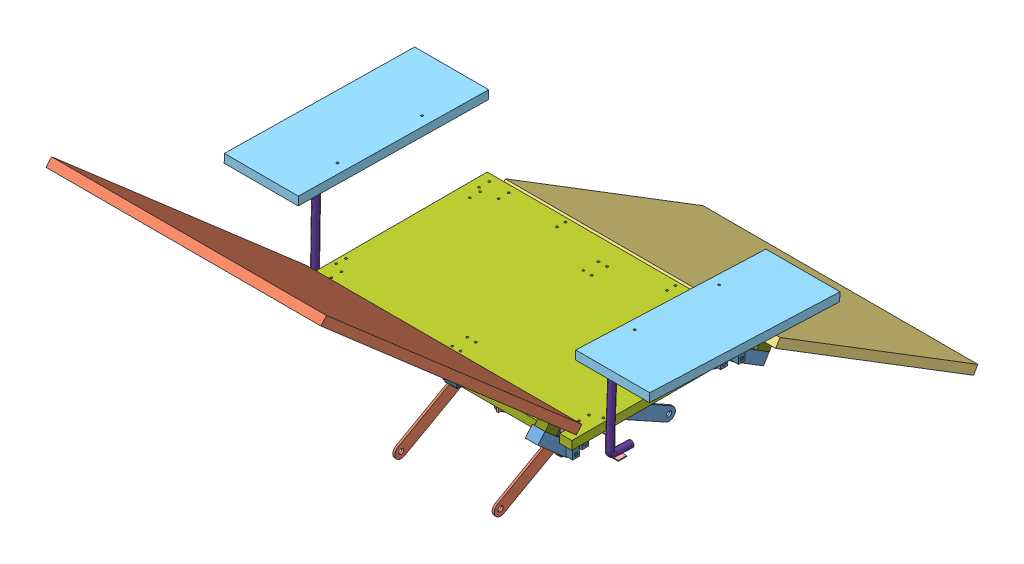
SolidWorks assembly shang, configuration 默认. Lengths in mm.
Overall size (1000 887.42 1553.51).
66 component instances, 23 part files, 0 mates.
Components (placement in the parent):
- 零件71-1: 零件71 [默认] at (-136.5896 263.2791 625.8551) x (0 -0.874201 0.485564) z (1 0 0) size (30 480 5)
- 零件7-5: 零件7 [默认] at (-126.5896 -56.9582 625.8551) x (0 0.874201 0.485564) z (-1 0 0) size (30 480 5)
- 零件7-6: 零件7 [默认] at (103.4104 -16.1101 648.5436) x (0 -0.874201 -0.485564) z (1 0 0) size (30 480 5)
- 零件71-3: 零件71 [默认] at (108.4104 263.2791 625.8551) x (0 -0.874201 0.485564) z (1 0 0) size (30 480 5)
- 滑块·1-3: 滑块·1 [默认] at (146.0969 224.4122 603.9442) x (1 0 0) z (0 1 0) size (20 28.9 7)
- 零件6-3: 零件6 [默认] at (80.2524 224.4122 600.5289) x (0 0 -1) z (0 -1 0) size (28.9 20 22)
- 滑轨-4: 滑轨 [默认] at (106.5244 234.4122 471.9365) x (-1 0 0) z (0 -1 0) size (10 150 6.5)
- 零件8-3: 零件8 [默认] at (126.9036 234.4122 204.8219) x (0 0 1) z (0 -1 0) size (30 20 32)
- 装配体5-1: 装配体5 [默认] at (-21.003 894.4122 308.3824) x (0 0 -1) z (0 -1 0) size (450 650 75.63)
  - 座板5-1: 座板5 [默认] at (-85.6176 9.4134 640) size (450 650 20)
  - 角度电机支架-1: 角度电机支架 [默认] at (41.3824 -11.5866 660) x (0 1 0) z (1 0 0) size (37 50 56)
  - spur gear_gb-1: spur gear_gb [GB - Spur gear 1M 32T 20PA 10FW ---S32A75H50L8.0N] at (110.3824 -265.5866 691.77) x (0 -1 0) z (-0.637461 0 0.770483) size (10 33.89 33.89)
  - spur gear_gb-2: spur gear_gb [GB - Spur gear 1M 32T 20PA 10FW ---S32A75H50L8.0N] at (78.3824 -265.5866 691.7667) x (0 -1 0) z (0 0 1) size (10 33.89 33.89)
  - 角电机减速机1-1: 角电机减速机1 [默认] at (69.2824 -6.5866 691.7667) x (1 0 0) z (0 -1 0) size (58.2 40 66)
  - 角度电机-1: 角度电机 [默认] at (40.1824 4.9134 693.7667) x (-1 0 0) z (0 -0.900769 -0.434299) size (74 31 31)
  - 联轴器2-1: 联轴器2 [默认] at (78.3824 -33.0866 691.7667) x (-0.028487 0 0.999594) z (0 1 0) size (16 16 40)
  - 轴-1: 轴 [默认] at (78.3824 -291.5866 691.7667) x (0.269951 0 -0.962874) z (0 1 0) size (8 8 251.5)
  - 支柱1-1: 支柱1 [默认] at (78.3824 -275.5866 660) x (1 0 0) z (0 -1 0) size (32 40 16)
  - 支柱1-2: 支柱1 [默认] at (110.3824 -285.5866 660) x (1 0 0) z (0 -1 0) size (32 40 16)
  - 支柱1-3: 支柱1 [默认] at (110.3824 -239.5866 660) x (1 0 0) z (0 -1 0) size (32 40 16)
  - 轴2-1: 轴2 [默认] at (110.3824 -239.5866 691.77) x (1 0 0) z (0 -1 0) size (8 8 62)
  - 联轴器2-5: 联轴器2 [默认] at (78.3824 46.9134 691.7667) x (-0.028487 0 0.999594) z (0 1 0) size (16 16 40)
  - 轴-5: 轴 [默认] at (78.3824 53.9134 691.7667) x (0.269951 0 -0.962874) z (0 1 0) size (8 8 251.5)
  - spur gear_gb-9: spur gear_gb [GB - Spur gear 1M 32T 20PA 10FW ---S32A75H50L8.0N] at (78.3824 279.4134 691.7667) x (0 1 0) z (0 0 -1) size (10 33.89 33.89)
  - 支柱1-13: 支柱1 [默认] at (78.3824 305.4134 660) x (1 0 0) z (0 -1 0) size (32 40 16)
  - 支柱1-14: 支柱1 [默认] at (110.3824 315.4134 660) x (1 0 0) z (0 -1 0) size (32 40 16)
  - 轴2-5: 轴2 [默认] at (110.3824 315.4134 691.77) x (1 0 0) z (0 -1 0) size (8 8 62)
  - spur gear_gb-10: spur gear_gb [GB - Spur gear 1M 32T 20PA 10FW ---S32A75H50L8.0N] at (110.3824 279.4134 691.77) x (0 1 0) z (0.637461 0 -0.770483) size (10 33.89 33.89)
  - 支柱1-15: 支柱1 [默认] at (110.3824 269.4134 660) x (1 0 0) z (0 -1 0) size (32 40 16)
  - 支柱1-16: 支柱1 [默认] at (-249.6176 -291.5866 660) x (-1 0 0) z (0 1 0) size (32 40 16)
  - 轴-6: 轴 [默认] at (-249.6176 -40.0866 691.7667) x (-0.269951 0 -0.962874) z (0 -1 0) size (8 8 251.5)
  - 联轴器2-6: 联轴器2 [默认] at (-249.6176 -33.0866 691.7667) x (0.028487 0 0.999594) z (0 -1 0) size (16 16 40)
  - 角度电机支架-3: 角度电机支架 [默认] at (-268.6176 -11.5866 660) x (0 1 0) z (1 0 0) size (37 50 56)
  - 角电机减速机1-3: 角电机减速机1 [默认] at (-240.5176 20.4134 691.7667) x (-1 0 0) z (0 1 0) size (58.2 40 66)
  - 角度电机-3: 角度电机 [默认] at (-211.4176 4.9134 693.7667) x (1 0 0) z (0 0.900769 0.434299) size (74 31 31)
  - spur gear_gb-11: spur gear_gb [GB - Spur gear 1M 32T 20PA 10FW ---S32A75H50L8.0N] at (-249.6176 -265.5866 691.7667) x (0 -1 0) z (0 0 -1) size (10 33.89 33.89)
  - 支柱1-17: 支柱1 [默认] at (-281.6176 -255.5866 660) x (-1 0 0) z (0 1 0) size (32 40 16)
  - 支柱1-18: 支柱1 [默认] at (-281.6176 -301.5866 660) x (-1 0 0) z (0 1 0) size (32 40 16)
  - 轴2-6: 轴2 [默认] at (-281.6176 -301.5866 691.77) x (-1 0 0) z (0 1 0) size (8 8 62)
  - 联轴器2-7: 联轴器2 [默认] at (-249.6176 46.9134 691.7667) x (0.028487 0 0.999594) z (0 -1 0) size (16 16 40)
  - 轴-7: 轴 [默认] at (-249.6176 305.4134 691.7667) x (-0.269951 0 -0.962874) z (0 -1 0) size (8 8 251.5)
  - spur gear_gb-12: spur gear_gb [GB - Spur gear 1M 32T 20PA 10FW ---S32A75H50L8.0N] at (-249.6176 279.4134 691.7667) x (0 1 0) z (0 0 1) size (10 33.89 33.89)
  - 支柱1-19: 支柱1 [默认] at (-249.6176 289.4134 660) x (-1 0 0) z (0 1 0) size (32 40 16)
  - 支柱1-20: 支柱1 [默认] at (-281.6176 299.4134 660) x (-1 0 0) z (0 1 0) size (32 40 16)
  - 支柱1-21: 支柱1 [默认] at (-281.6176 253.4134 660) x (-1 0 0) z (0 1 0) size (32 40 16)
  - 轴2-7: 轴2 [默认] at (-281.6176 253.4134 691.77) x (-1 0 0) z (0 1 0) size (8 8 62)
  - spur gear_gb-13: spur gear_gb [GB - Spur gear 1M 32T 20PA 10FW ---S32A75H50L8.0N] at (-281.6176 -275.5866 691.77) x (0 1 0) z (0.089959 0 0.995946) size (10 33.89 33.89)
  - spur gear_gb-15: spur gear_gb [GB - Spur gear 1M 32T 20PA 10FW ---S32A75H50L8.0N] at (-281.6176 289.4134 691.77) x (0 -1 0) z (-0.089959 0 -0.995946) size (10 33.89 33.89)
- 垫块1-1: 垫块1 [默认] at (-294.0896 193.1422 122.1756) x (-1 0 0) z (0 -0.850742 0.525584) size (25 35 18.77)
- 扶手1-1: 扶手1 [默认] at (-360.0896 202.2551 503.1223) x (0 -0.015709 -0.999877) z (1 0 0) size (307.5 215 15)
- 扶手旋转-1: 扶手旋转 [默认] at (-313.6259 203.5669 503.1211) size (50 42 20)
- 扶手1-3: 扶手1 [默认] at (336.9104 202.0087 503.1292) x (0 -0.040351 -0.999186) z (1 0 0) size (307.5 215 15)
- 垫块1-6: 垫块1 [默认] at (265.9104 177.1738 132.0408) x (1 0 0) z (0 0.850742 -0.525584) size (25 35 18.77)
- 垫块1-7: 垫块1 [默认] at (-294.0896 272.2161 621.6078) x (1 0 0) z (0 -0.754696 0.656075) size (25 35 18.77)
- 转动装置1-1: 转动装置1 [默认] at (-291.5896 220.3563 610.3768) x (0 0.656075 0.754696) z (-1 0 0) size (100 26 30)
- 转动装置1-2: 转动装置1 [默认] at (-291.5896 188.4515 175.03) x (0 -0.525584 -0.850742) z (-1 0 0) size (100 26 30)
- 靠背板2-1: 靠背板2 [默认] at (-11.5896 523.1649 910.2789) x (0 0.656075 0.754696) z (0 0.754696 -0.656075) size (800 650 20)
- 转动装置1-3: 转动装置1 [默认] at (263.4104 188.4515 175.03) x (0 -0.525584 -0.850742) z (-1 0 0) size (100 26 30)
- 垫块1-8: 垫块1 [默认] at (265.9104 177.1738 132.0408) x (1 0 0) z (0 0.850742 -0.525584) size (25 35 18.77)
- 转动装置1-4: 转动装置1 [默认] at (263.4104 220.3563 610.3768) x (0 0.656075 0.754696) z (-1 0 0) size (100 26 30)
- 垫块1-9: 垫块1 [默认] at (265.9104 258.0505 633.9224) x (-1 0 0) z (0 0.754696 -0.656075) size (25 35 18.77)
- 曲腿板2-2: 曲腿板2 [默认] at (-11.5896 74.8193 -107.4021) x (0 0.525584 0.850742) z (0 -0.850742 0.525584) size (550 650 20)
- 扶手定位1-1: 扶手定位1 [默认] at (-325.3593 195.5519 525.1121) size (50 41.5 20)
- 扶手定位1-2: 扶手定位1 [默认] at (302.1801 195.5519 545.1121) x (-1 0 0) z (0 0 -1) size (50 41.5 20)
- 扶手板1-1: 扶手板1 [默认] at (-424.0896 404.6988 390.8082) x (0 -0.015709 -0.999877) z (0 0.999877 -0.015709) size (450 175 20)
- 扶手板1-2: 扶手板1 [默认] at (400.9104 426.2352 384.8652) x (0 -0.040351 -0.999186) z (0 -0.999186 0.040351) size (450 175 20)
